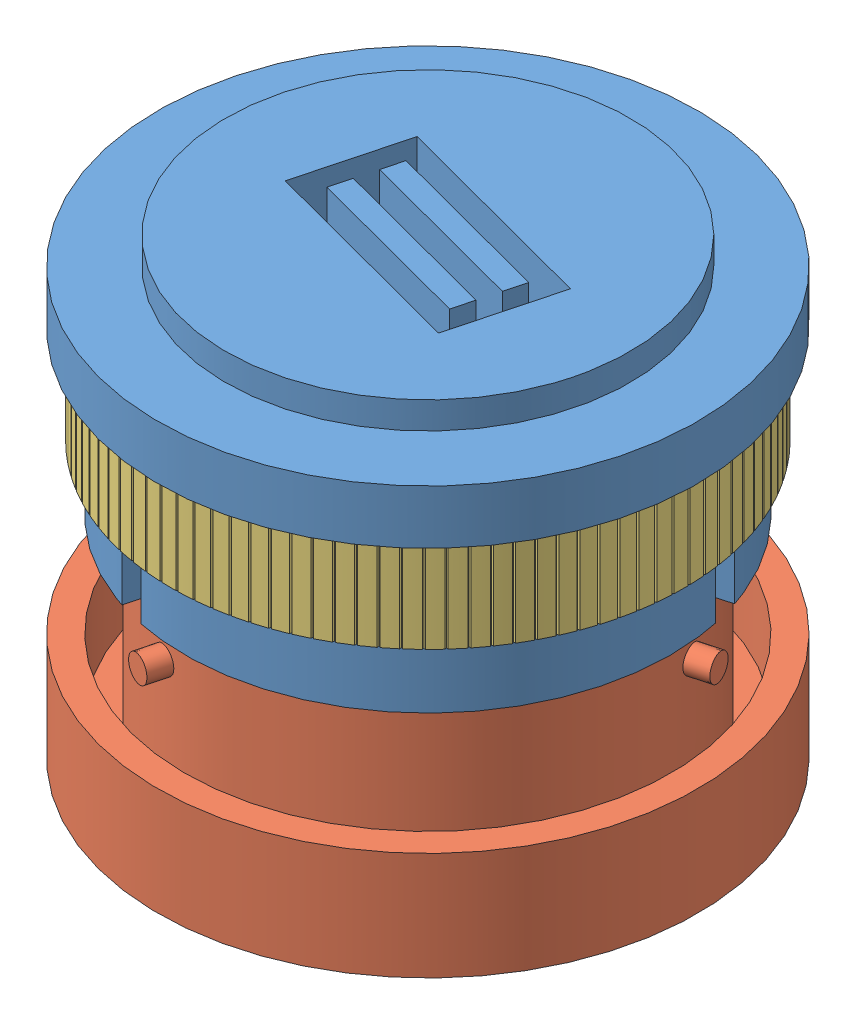
SolidWorks assembly Connector Assembly, configuration Default. Lengths in mm.
Overall size (122.25 84 122.25).
3 component instances, 3 part files, 13 mates.
Components (placement in the parent):
- Conector female-1: Conector female [Default] x (0 -1 0) z (0.96675 0 0.255724) size (45 100 100)
- Conector male-1: Conector male [Default] at (0 -74 0) x (0 1 0) z (-0.255724 0 0.96675) size (38 100 100)
- Lock-1: Lock [Default] at (0 -17 0) x (0.020654 0 0.999787) z (0 1 0) size (95 95 17)
Mates (geometry in assembly coordinates):
- Coincident1: coincident anti-aligned: plane of Conector female-1; plane of assembly through (0 0 0) normal (0 1 0)
- Coincident2: coincident: axis of Conector female-1 through (0 -5 0) axis (0 1 0); plane of assembly
- Coincident3: coincident: axis of Conector female-1 through (0 -5 0) axis (0 1 0); plane of assembly
- Coincident4: coincident anti-aligned: axis of Conector female-1 through (0 -5 0) axis (0 1 0); axis of Conector male-1 through (0 -36 0) axis (0 -1 0)
- PathMate2: path: point of Conector male-1; line of Conector female-1 through (0 -55 0) axis (0 1 0); plane of Conector female-1 through (-15.2031 0 47.6982) normal (0.96675 0 0.255724)
- LimitDistance1: limit distance = 31 mm anti-aligned: plane of Conector male-1 through (0 -36 0) normal (0 1 0); plane of Conector female-1 through (0 -5 0) normal (0 -1 0)
- InPlace1: in place: plane of ? through (-45.733 0 20.3653) normal (0.451909 0 0.892064); plane of ? through (-1.1298 0 -2.2302) normal (0.451909 0 0.892064); moOrthogonalPlaneRef_w of ? through (-45.733 0 20.3653) normal (0.451909 0 0.892064); unknown of ?; plane of ? through (-45.733 0 20.3653) normal (0.451909 0 0.892064); plane of ? through (-1.1298 0 -2.2302) normal (0.892064 0 -0.451909); unknown of ?; unknown of ?
- Coincident5: coincident aligned: plane of Conector female-1; plane of ?
- Coincident6: coincident aligned: moOrthogonalPlaneRef_w of Conector female-1 through (-1.1298 0 -2.2302) normal (-0.892064 0 0.451909); plane of ?
- Coincident7: coincident anti-aligned: moOrthogonalPlaneRef_w of Conector female-1 through (-1.1298 0 -2.2302) normal (0 -1 0); plane of ?
- Coincident11: coincident aligned: axis of Conector female-1 through (0 -5 0) axis (0 1 0); axis of Lock-1 through (0 -23 0) axis (0 1 0)
- Width1: width aligned: plane of Lock-1 through (0 -16 0) normal (0 1 0); plane of Lock-1 through (0 -18 0) normal (0 -1 0); plane of Conector female-1 through (-35.4684 -18 -35.2419) normal (0 1 0); plane of Conector female-1 through (-35.4684 -16 -35.2419) normal (0 -1 0)
- LimitAngle2: limit planar angle = 0.244346 rad anti-aligned: plane of Conector female-1 through (-7.9525 0 49.6161) normal (-0.96675 0 -0.255724); plane of Lock-1 through (4.3808 -16 2.41) normal (0.876168 0 0.482006)
